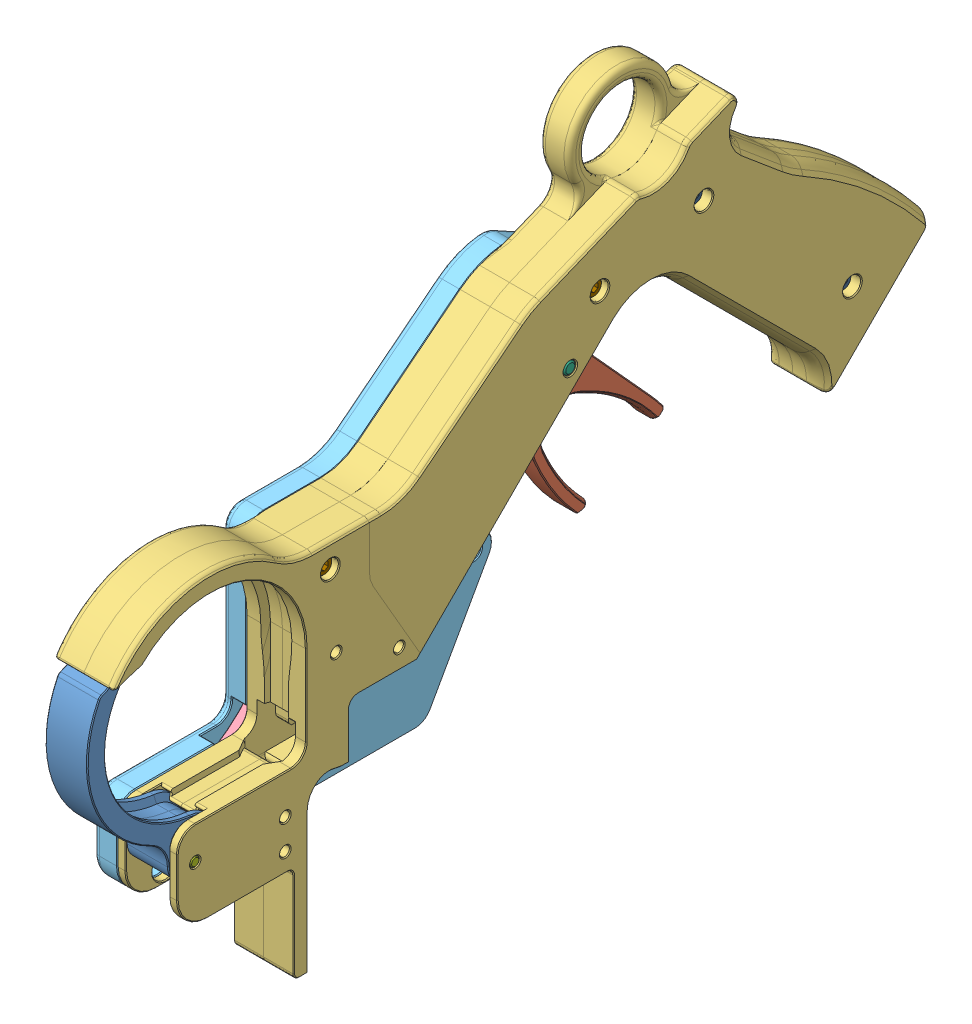
SolidWorks assembly Jaw Mechanism, configuration Default. Lengths in mm.
Overall size (27.84 198.75 278.93).
24 component instances, 11 part files, 0 mates.
Components (placement in the parent):
- Lower Jaw^Zip Tie Installer-1: Lower Jaw^Zip Tie Installer [Default] at origin size (14.21 80.48 47.55)
- Trigger^Zip Tie Installer-1: Trigger^Zip Tie Installer [Default] at origin size (8 68.11 68.05)
- Main Casing^Zip Tie Installer-1: Main Casing^Zip Tie Installer [Default] at origin size (20.94 198.75 273.05)
- Jaw Link^Zip Tie Installer-1: Jaw Link^Zip Tie Installer [Default] at origin size (10.4 114.15 109.74)
- Trigger Link Cover^Zip Tie Installer-1: Trigger Link Cover^Zip Tie Installer [Default] at origin size (7.8 125.13 144.29)
- Dowel Pin 4mm(20mm)-1: Dowel Pin 4mm(20mm) [Default] at (0 37 -120) x (0 0 1) z (-1 0 0) size (4 4 20)
- Dowel Pin 3mm(20mm)-1: Dowel Pin 3mm(20mm) [Default] at (0 -43 5) x (0 0 1) z (-1 0 0) size (3 3 20)
- Dowel Pin 3mm(20mm)-2: Dowel Pin 3mm(20mm) [Default] at (-4.4 51.9102 -106.6701) x (0 0 1) z (-1 0 0) size (3 3 20)
- Dowel Pin 3mm(20mm)-3: Dowel Pin 3mm(20mm) [Default] at (-4.4 -54.2415 -4.9312) x (0 0 1) z (-1 0 0) size (3 3 20)
- Extension Spring(32mm)-1: Extension Spring(32mm) [Default] at (-1.4 -3.9622 -71.1832) x (0 -0.766044 -0.642788) z (1 0 0) size (6.36 36.59 6.36)
- socket head cap screw_am(B18.3.1M - 3 x 0.5 x 20 Hex SHCS -- 20NHX)-1: socket head cap screw_am(B18.3.1M - 3 x 0.5 x 20 Hex SHCS -- 20NHX) [Default] at (8 19 -40) x (-1 0 0) z (0 0 1) size (23 5.5 5.5)
- socket head cap screw_am(B18.3.1M - 3 x 0.5 x 20 Hex SHCS -- 20NHX)-2: socket head cap screw_am(B18.3.1M - 3 x 0.5 x 20 Hex SHCS -- 20NHX) [Default] at (8 54.3811 -129.8944) x (-1 0 0) z (0 0 -1) size (23 5.5 5.5)
- socket head cap screw_am(B18.3.1M - 3 x 0.5 x 8 Hex SHCS -- 8NHX)-1: socket head cap screw_am(B18.3.1M - 3 x 0.5 x 8 Hex SHCS -- 8NHX) [Default] at (-4.8 14.0359 -92.6324) x (1 0 0) z (0 0 -1) size (11 5.5 5.5)
- socket head cap screw_am(B18.3.1M - 3 x 0.5 x 8 Hex SHCS -- 8NHX)-2: socket head cap screw_am(B18.3.1M - 3 x 0.5 x 8 Hex SHCS -- 8NHX) [Default] at (7 13.6655 -214.0452) x (-1 0 0) z (0 0 1) size (11 5.5 5.5)
- socket head cap screw_am(B18.3.1M - 3 x 0.5 x 8 Hex SHCS -- 8NHX)-3: socket head cap screw_am(B18.3.1M - 3 x 0.5 x 8 Hex SHCS -- 8NHX) [Default] at (-4.8 -6.5333 -68.119) x (1 0 0) z (0 0 -1) size (11 5.5 5.5)
- socket head cap screw_am(B18.3.1M - 3 x 0.5 x 8 Hex SHCS -- 8NHX)-4: socket head cap screw_am(B18.3.1M - 3 x 0.5 x 8 Hex SHCS -- 8NHX) [Default] at (7 63.163 -164.5477) x (-1 0 0) z (0 0 1) size (11 5.5 5.5)
- 94180A331_HEAT-SET INSERTS FOR PLASTICS-1: 94180A331_HEAT-SET INSERTS FOR PLASTICS [Default] at (-10 54.3811 -129.8944) x (0 -1 0) z (0 0 1) size (5.56 4.12 5.56)
- 94180A331_HEAT-SET INSERTS FOR PLASTICS-2: 94180A331_HEAT-SET INSERTS FOR PLASTICS [Default] at (-10 -15 -63) x (0 -1 0) z (0 0 1) size (5.56 4.12 5.56)
- 94180A331_HEAT-SET INSERTS FOR PLASTICS-3: 94180A331_HEAT-SET INSERTS FOR PLASTICS [Default] at (-10 -6 -42) x (0 -1 0) z (0 0 1) size (5.56 4.12 5.56)
- 94180A331_HEAT-SET INSERTS FOR PLASTICS-4: 94180A331_HEAT-SET INSERTS FOR PLASTICS [Default] at (0 63.163 -164.5477) x (0 -1 0) z (0 0 1) size (5.56 4.12 5.56)
- 94180A331_HEAT-SET INSERTS FOR PLASTICS-5: 94180A331_HEAT-SET INSERTS FOR PLASTICS [Default] at (-10 19 -40) x (0 -1 0) z (0 0 1) size (5.56 4.12 5.56)
- 94180A331_HEAT-SET INSERTS FOR PLASTICS-6: 94180A331_HEAT-SET INSERTS FOR PLASTICS [Default] at (0 -45 -25) x (0 -1 0) z (0 0 1) size (5.56 4.12 5.56)
- 94180A331_HEAT-SET INSERTS FOR PLASTICS-7: 94180A331_HEAT-SET INSERTS FOR PLASTICS [Default] at (-10 -55 -25) x (0 -1 0) z (0 0 1) size (5.56 4.12 5.56)
- 94180A331_HEAT-SET INSERTS FOR PLASTICS-8: 94180A331_HEAT-SET INSERTS FOR PLASTICS [Default] at (0 13.6655 -214.0452) x (0 -1 0) z (0 0 1) size (5.56 4.12 5.56)
